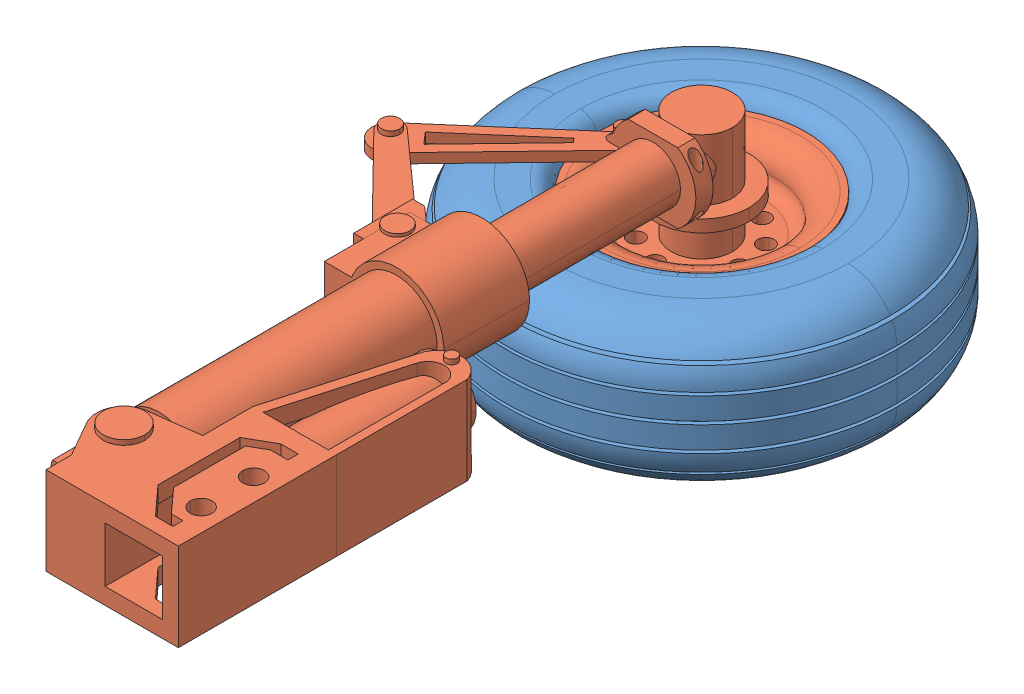
SolidWorks assembly Landing gear assembly, configuration Default. Lengths in mm.
Overall size (137.21 80.09 297.16).
2 component instances, 2 part files, 0 mates.
Components (placement in the parent):
- Landing gear tire-1: Landing gear tire [Default] at (41.2481 74.6537 108.5035) size (137.21 51.51 137.21)
- Langing gear-1: Langing gear [Default] at (41.1897 73.9625 108.2807) size (107.12 80.09 265.25)
